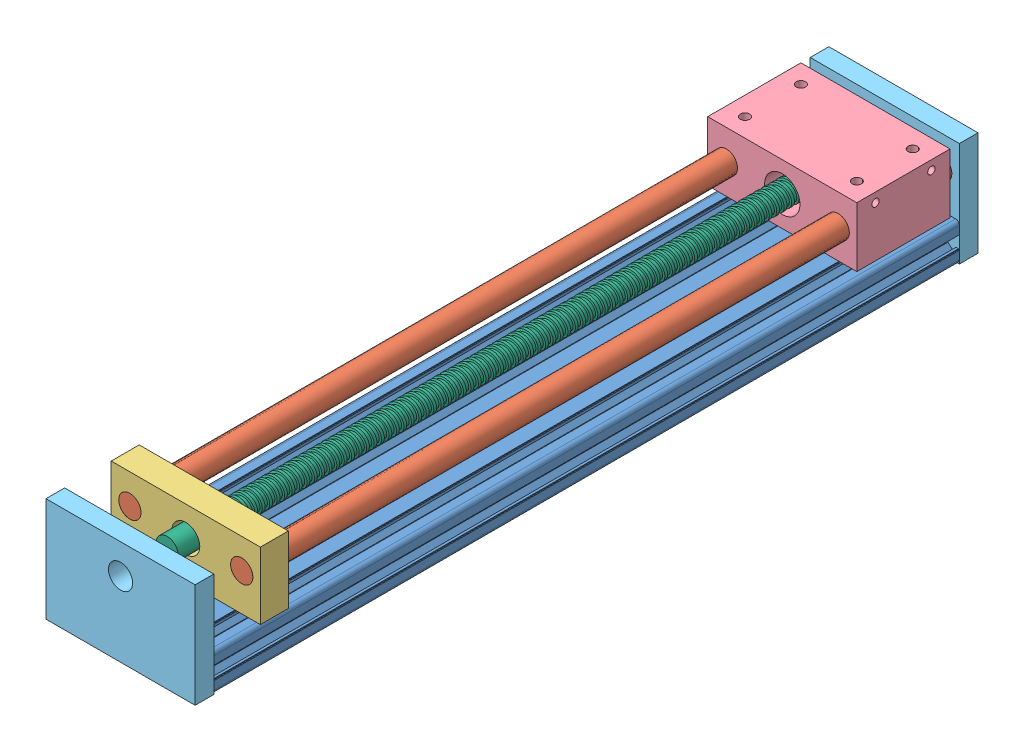
SolidWorks assembly 丝杠导轨, configuration 默认. Lengths in mm.
8 component instances, 6 part files, 19 mates.
Components (placement in the parent):
- 2080_400mm_底座-1: 2080_400mm_底座 [默认] at (-180.716 93.3398 172.4205) size (80 20 400)
- 滑轨-1: 滑轨 [默认] at (-180.716 123.3398 172.4205) size (12 12 375)
- 滑轨-2: 滑轨 [默认] at (-120.716 123.3398 172.4205) size (12 12 375)
- 零件2-1: 零件2 [默认] at (-160.0493 118.4509 532.4205) size (80 36 15)
- 零件3-1: 零件3 [默认] at (-190.716 126.4666 202.9802) x (0 0 -1) z (1 0 0) size (50 32 80)
- 零件4-1: 零件4 [默认] at (-154.6031 110.7504 162.4205) size (80 56 10)
- 丝杆-1: 丝杆 [默认] at (-150.716 123.3398 162.4205) x (0.727313 -0.686306 0) z (0 0 1) size (12.1 12.1 395)
- 零件4-2: 零件4 [默认] at (-154.6031 110.7504 572.4205) size (80 56 10)
Mates (geometry in assembly coordinates):
- 同心2: concentric: cylinder of 零件2-1 through (-150.716 123.3398 547.4205) axis (0 0 -1) radius 7.5; cylinder of 丝杆-1 through (-150.716 123.3398 532.4205) axis (0 0 -1) radius 6
- 同心3: concentric: cylinder of 滑轨-2 through (-120.716 123.3398 547.4205) axis (0 0 -1) radius 6; cylinder of 零件2-1 through (-120.716 123.3398 547.4205) axis (0 0 -1) radius 6
- 重合4: coincident: plane of 滑轨-2 through (-120.716 123.3398 547.4205) normal (0 0 1); plane of 零件2-1 through (-160.0493 118.4509 547.4205) normal (0 0 1)
- 同心4: concentric: cylinder of 滑轨-1 through (-180.716 123.3398 547.4205) axis (0 0 -1) radius 6; cylinder of 零件2-1 through (-180.716 123.3398 547.4205) axis (0 0 -1) radius 6
- 重合5: coincident: plane of 滑轨-1 through (-180.716 123.3398 547.4205) normal (0 0 1); plane of 零件2-1 through (-160.0493 118.4509 547.4205) normal (0 0 1)
- 重合7: coincident: plane of 2080_400mm_底座-1 through (-180.716 93.3398 172.4205) normal (0 0 -1); plane of 零件4-1 through (-154.6031 110.7504 172.4205) normal (0 0 1)
- 重合8: coincident: plane of 2080_400mm_底座-1 through (-110.716 96.9398 572.4205) normal (1 0 0); plane of 零件4-1 through (-110.716 139.3398 172.4205) normal (1 0 0)
- 重合9: coincident: plane of 2080_400mm_底座-1 through (-128.016 83.3398 572.4205) normal (0 -1 0); plane of 零件4-1 through (-190.716 83.3398 172.4205) normal (0 -1 0)
- 重合10: coincident: plane of 零件4-1 through (-154.6031 110.7504 162.4205) normal (0 0 -1); plane of 丝杆-1 through (-150.716 123.3398 162.4205) normal (0 0 -1)
- 同心5: concentric: cylinder of 零件3-1 through (-150.716 123.3398 147.4205) axis (0 0 1) radius 9.5; cylinder of 丝杆-1 through (-150.716 123.3398 532.4205) axis (0 0 -1) radius 6
- 同心6: concentric: cylinder of 滑轨-1 through (-180.716 123.3398 547.4205) axis (0 0 -1) radius 6; cylinder of 零件3-1 through (-180.716 123.3398 147.4205) axis (0 0 1) radius 6
- 平行1: parallel: plane of 2080_400mm_底座-1 through (-133.416 103.3398 572.4205) normal (0 1 0); plane of 零件2-1 through (-190.716 103.3398 547.4205) normal (0 -1 0)
- 螺旋1: screw = 5 mm: cylinder of 零件3-1 through (-150.716 123.3398 147.4205) axis (0 0 1) radius 9.5; cylinder of 丝杆-1 through (-150.716 123.3398 532.4205) axis (0 0 -1) radius 6
- LimitDistance1: limit distance = 305 mm: plane of 零件3-1 through (-110.716 139.3398 227.4205) normal (0 0 1); plane of 零件2-1 through (-160.0493 118.4509 532.4205) normal (0 0 -1)
- 重合11: coincident: plane of 2080_400mm_底座-1 through (-180.716 93.3398 572.4205) normal (0 0 1); plane of 零件4-2 through (-154.6031 110.7504 572.4205) normal (0 0 -1)
- 重合12: coincident: plane of 2080_400mm_底座-1 through (-110.716 96.9398 572.4205) normal (1 0 0); plane of 零件4-2 through (-110.716 139.3398 582.4205) normal (1 0 0)
- 重合13: coincident: plane of 2080_400mm_底座-1 through (-148.016 83.3398 572.4205) normal (0 -1 0); plane of 零件4-2 through (-190.716 83.3398 582.4205) normal (0 -1 0)
- 距离1: distance = 25 mm: plane of 零件4-2 through (-154.6031 110.7504 572.4205) normal (0 0 -1); plane of 零件2-1 through (-160.0493 118.4509 547.4205) normal (0 0 1)
- 同心7: concentric: cylinder of 丝杆-1 through (-150.716 123.3398 532.4205) axis (0 0 -1) radius 6; cylinder of 零件4-2 through (-150.716 123.3398 582.4205) axis (0 0 -1) radius 6.5
